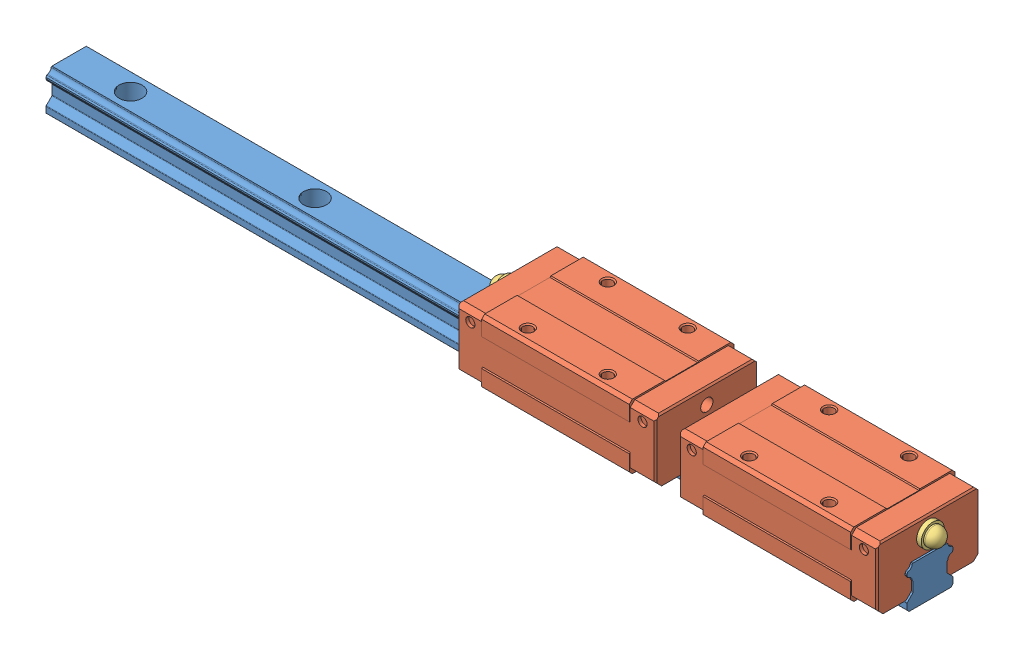
SolidWorks assembly Rails 280mm 2 block SHS15, configuration По умолчанию. Lengths in mm.
Overall size (284.4 24 34).
5 component instances, 3 part files, 10 mates.
Components (placement in the parent):
- SHS15V280A-1: SHS15V280A [По умолчанию] at origin size (280 13 15)
- SHS15VUU-1: SHS15VUU [По умолчанию] at (227.2 3 0) size (64.4 21 34)
- SHS15VUU-2: SHS15VUU [По умолчанию] at (155.2 3 0) size (64.4 21 34)
- PB1021B-SHS_grease_nipple-1: PB1021B-SHS_grease_nipple [По умолчанию] at (123 18.5 0) size (9.5 7.5 7.5)
- PB1021B-SHS_grease_nipple-2: PB1021B-SHS_grease_nipple [По умолчанию] at (259.4 18.5 0) x (-1 0 0) z (0 -1 0) size (9.5 7.5 7.5)
Mates (geometry in assembly coordinates):
- Concentric1: concentric aligned: cylinder of SHS15V280A-1 through (260 12.8797 -7.2295) axis (-1 0 0) radius 1.4307; cylinder of SHS15VUU-1 through (260.4 12.8797 -7.2295) axis (-1 0 0) radius 1.4307
- Concentric2: concentric aligned: cylinder of SHS15V280A-1 through (260 12.8797 7.2295) axis (-1 0 0) radius 1.4307; cylinder of SHS15VUU-1 through (260.4 12.8797 7.2295) axis (-1 0 0) radius 1.4307
- Concentric3: concentric aligned: cylinder of SHS15V280A-1 through (260 12.8797 -7.2295) axis (-1 0 0) radius 1.4307; cylinder of SHS15VUU-2 through (188.4 12.8797 -7.2295) axis (-1 0 0) radius 1.4307
- Concentric4: concentric aligned: cylinder of SHS15V280A-1 through (260 12.8797 7.2295) axis (-1 0 0) radius 1.4307; cylinder of SHS15VUU-2 through (188.4 12.8797 7.2295) axis (-1 0 0) radius 1.4307
- Concentric5: concentric aligned: cylinder of SHS15VUU-2 through (128.5 18.5 0) axis (1 0 0) radius 2; cylinder of PB1021B-SHS_grease_nipple-1 through (128.5 18.5 0) axis (1 0 0) radius 2
- Coincident1: coincident anti-aligned: plane of SHS15VUU-2 through (124 3 0) normal (-1 0 0); plane of PB1021B-SHS_grease_nipple-1 through (124 22.25 0) normal (1 0 0)
- Concentric6: concentric anti-aligned: cylinder of SHS15VUU-1 through (260.4 18.5 0) axis (1 0 0) radius 2; cylinder of PB1021B-SHS_grease_nipple-2 through (255.9 18.5 0) axis (-1 0 0) radius 2
- Coincident2: coincident anti-aligned: plane of SHS15VUU-1 through (260.4 3 0) normal (1 0 0); plane of PB1021B-SHS_grease_nipple-2 through (260.4 18.5 -3.75) normal (-1 0 0)
- Distance1: distance = 120 mm anti-aligned: plane of SHS15VUU-1 through (251.2 3 0) normal (1 0 0); plane of SHS15VUU-2 through (131.2 3 0) normal (-1 0 0)
- Distance2: limit distance = 143 mm aligned: plane of SHS15VUU-2 through (123 3 0) normal (-1 0 0); plane of SHS15V280A-1 through (-20 2.5703 7.1871) normal (-1 0 0)
